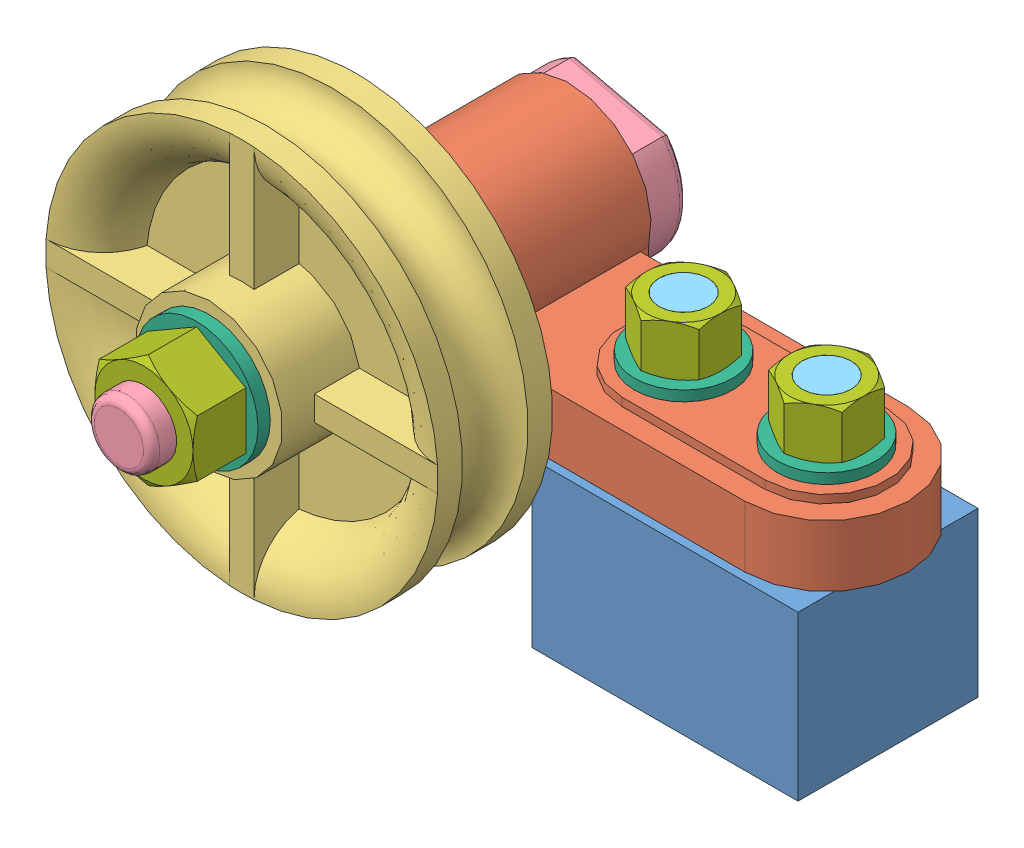
SolidWorks assembly Assem, configuration Default. Lengths in mm.
Overall size (153.8 108.7 126.06).
12 component instances, 7 part files, 22 mates.
Components (placement in the parent):
- Part2-1: Part2 [Default] at (45.3584 8.1663 59.742) size (65 40 44)
- Part5-1: Part5 [Default] at (15.8964 68.1663 31.0894) x (1 0 0.000903) z (-0.000903 0 1) size (125 40 44)
- Part7-1: Part7 [Default] at (-33.6231 68.1663 89.8911) x (1 0 0.000903) z (0 -1 0) size (97.4 103.79 97.4)
- Part9-1: Part9 [Default] at (-34.546 100.184 21.0438) x (0.223963 0.974598 0.000202) z (-0.000903 0 1) size (30 38 120)
- Part25-1: Part25 [Default] at (23.8336 44.8663 62.9362) size (12 35 12)
- Part25-2: Part25 [Default] at (58.8335 44.8663 62.9678) size (12 35 12)
- plain washer normal grade a_iso-1: plain washer normal grade a_iso [Washer ISO 7089 - 12] at (8.0674 65.1663 53.0824) x (0 -1 0) z (0 0 1) size (2.5 24 24)
- plain washer normal grade a_iso-2: plain washer normal grade a_iso [Washer ISO 7089 - 12] at (43.0674 65.1663 53.114) x (0 -1 0) z (0 0 1) size (2.5 24 24)
- hex nut gradec_iso-1: hex nut gradec_iso [ISO - 4034 - M12 - N] at (8.0674 67.6663 53.0824) x (1 0 0) z (0 -1 0) size (18 20.78 12.2)
- hex nut gradec_iso-2: hex nut gradec_iso [ISO - 4034 - M12 - N] at (43.0674 67.6663 53.114) x (1 0 0) z (0 -1 0) size (18 20.78 12.2)
- hex nut gradec_iso-3: hex nut gradec_iso [ISO - 4034 - M16 - N] at (-42.0065 68.1663 134.9371) x (1 0 0.000903) z (-0.000903 0 1) size (24 27.71 15.9)
- plain washer normal grade a_iso-4: plain washer normal grade a_iso [Washer ISO 7089 - 16] at (-41.9922 68.1663 119.0372) x (0.000903 0 -1) z (1 0 0.000903) size (3 30 30)
Mates (geometry in assembly coordinates):
- Coincident2: coincident aligned: circle of Part5-1; circle of Part2-1
- Concentric4: concentric aligned: cylinder of Part5-1 through (-41.9524 68.1663 75.0372) axis (0.000903 0 -1) radius 20; cylinder of Part9-1 through (-41.9922 68.1663 119.0372) axis (0.000903 0 -1) radius 11
- Coincident3: coincident aligned: circle of Part5-1; plane of Part9-1 through (-34.555 100.184 31.0438) normal (-0.000903 0 1)
- Concentric11: concentric anti-aligned: cylinder of Part7-1 through (-42.0175 68.1663 147.0358) axis (-0.000903 0 1) radius 9; cylinder of Part9-1 through (-41.9922 68.1663 119.0372) axis (0.000903 0 -1) radius 11
- Coincident4: coincident anti-aligned: plane of Part5-1 through (15.8567 68.1663 75.0894) normal (-0.000903 0 1); plane of Part7-1 through (-33.6097 68.1663 75.0447) normal (0.000903 0 -1)
- Coincident6: coincident anti-aligned: plane of Part5-1 through (15.8964 65.1663 31.0894) normal (0 1 0); plane of plain washer normal grade a_iso-1 through (14.5674 65.1663 53.0824) normal (0 -1 0)
- Concentric16: concentric aligned: circle of Part5-1; circle of plain washer normal grade a_iso-1
- Coincident9: coincident anti-aligned: plane of Part5-1 through (15.8964 65.1663 31.0894) normal (0 1 0); plane of plain washer normal grade a_iso-2 through (49.5674 65.1663 53.114) normal (0 -1 0)
- Concentric17: concentric aligned: circle of Part5-1; circle of plain washer normal grade a_iso-2
- Coincident10: coincident anti-aligned: plane of plain washer normal grade a_iso-1 through (20.0674 67.6663 53.0824) normal (0 1 0); plane of hex nut gradec_iso-1 through (-9.9326 67.6663 53.0824) normal (0 -1 0)
- Concentric18: concentric anti-aligned: circle of plain washer normal grade a_iso-1; circle of hex nut gradec_iso-1
- Coincident11: coincident anti-aligned: plane of plain washer normal grade a_iso-2 through (55.0674 67.6663 53.114) normal (0 1 0); plane of hex nut gradec_iso-2 through (25.0674 67.6663 53.114) normal (0 -1 0)
- Concentric19: concentric aligned: circle of plain washer normal grade a_iso-2; circle of hex nut gradec_iso-2
- Concentric20: concentric aligned: cylinder of Part25-1 through (8.0674 79.8663 53.0824) axis (0 -1 0) radius 6; cylinder of hex nut gradec_iso-1 through (8.0674 79.8663 53.0824) axis (0 -1 0) radius 5.1
- Concentric21: concentric anti-aligned: circle of Part25-1; circle of hex nut gradec_iso-1
- Coincident12: coincident aligned: circle of Part25-1; circle of hex nut gradec_iso-1
- Concentric22: concentric anti-aligned: circle of Part25-2; circle of hex nut gradec_iso-2
- Concentric26: concentric anti-aligned: cylinder of Part9-1 through (-42.0121 68.1663 141.0371) axis (0.000903 0 -1) radius 8; cylinder of hex nut gradec_iso-3 through (-41.9922 68.1663 119.0372) axis (-0.000903 0 1) radius 7
- Concentric27: concentric aligned: circle of Part9-1; circle of hex nut gradec_iso-3
- Coincident18: coincident anti-aligned: plane of Part9-1 through (-34.6345 100.184 119.0438) normal (-0.000903 0 1); plane of hex nut gradec_iso-3 through (-41.9922 82.0227 119.0372) normal (0.000903 0 -1)
- Coincident19: coincident anti-aligned: plane of Part7-1 through (-33.6494 68.1663 119.0447) normal (-0.000903 0 1); plane of plain washer normal grade a_iso-4 through (-41.9922 76.6663 119.0372) normal (0.000903 0 -1)
- Concentric30: concentric aligned: circle of Part9-1; circle of plain washer normal grade a_iso-4
